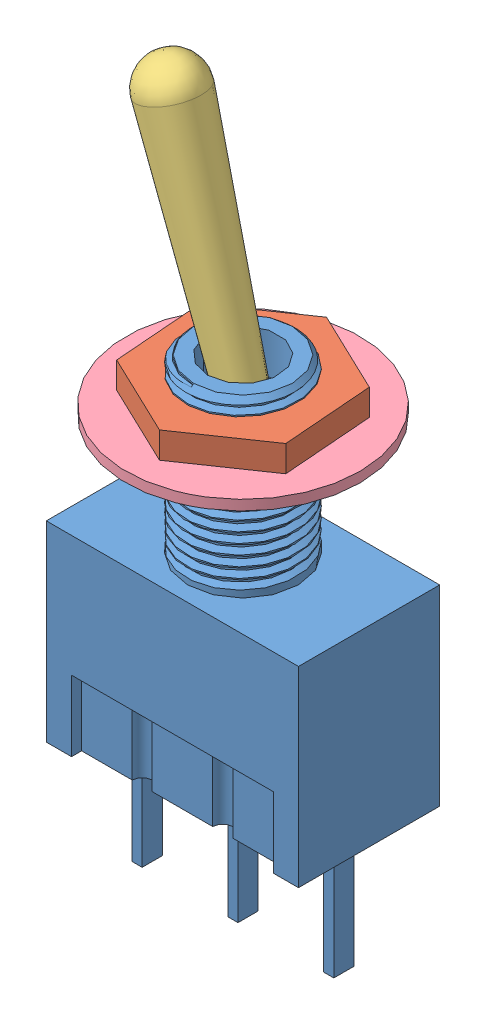
SolidWorks assembly toggle_mts1_assembly, configuration Default. Lengths in mm.
Overall size (15.55 36.55 15.55).
4 component instances, 4 part files, 7 mates.
Components (placement in the parent):
- toggle_mts_1_base_thread-1: toggle_mts_1_base_thread [Default] at origin size (12.5 25.17 7)
- toggle_mts_1_nut-1: toggle_mts_1_nut [Default] at (0 15.8967 -0.4087) x (-0.07757 0 -0.996987) z (0.996987 0 -0.07757) size (9.01 1.63 7.8)
- toggle_mts_1_lever-1: toggle_mts_1_lever [Default] at (0 16.1983 -0.4087) x (0 0 1) z (-0.956305 -0.292372 0) size (3 13.5 3)
- toggle_mts_1_washer-1: toggle_mts_1_washer [Default] at (0 15.3967 -0.4087) x (0.895652 0 -0.444756) z (0.444756 0 0.895652) size (11.6 0.5 11.6)
Mates (geometry in assembly coordinates):
- Screw1: screw = 0.5 aligned: line of toggle_mts_1_base_thread-1 through (0 17.7 -0.4087) axis (0 -1 0); line of toggle_mts_1_nut-1 through (0 17.1967 -0.4087) axis (0 -1 0)
- Coincident2: coincident anti-aligned: line of toggle_mts_1_base_thread-1 through (0 16.1983 0) axis (0 0 -1); line of toggle_mts_1_lever-1 through (0 16.1983 -1.4087) axis (0 0 1)
- Coincident3: coincident: line of toggle_mts_1_lever-1 through (-3.5085 27.6739 -0.4087) axis (0.292372 -0.956305 0); plane of assembly through (0 0 -0.4087) normal (0 0 -1)
- LimitAngle2: limit planar angle = 0.296706 rad aligned: line of toggle_mts_1_lever-1 through (-3.5085 27.6739 -0.4087) axis (0.292372 -0.956305 0); line of toggle_mts_1_base_thread-1 through (0 17.7 -0.4087) axis (0 -1 0)
- Concentric1: concentric aligned: cylinder of toggle_mts_1_base_thread-1 through (0 18 -0.4087) axis (0 -1 0) radius 2.75; cylinder of toggle_mts_1_washer-1 through (0 15.8967 -0.4087) axis (0 -1 0) radius 2.85
- Coincident6: coincident anti-aligned: plane of toggle_mts_1_nut-1 through (0 15.8967 -0.4087) normal (0 -1 0); plane of toggle_mts_1_washer-1 through (0 15.8967 -0.4087) normal (0 1 0)
- LimitDistance1: limit distance = 5.8967 mm anti-aligned: plane of toggle_mts_1_washer-1 through (0 15.3967 -0.4087) normal (0 -1 0); plane of toggle_mts_1_base_thread-1 through (0 9.5 0) normal (0 1 0)
